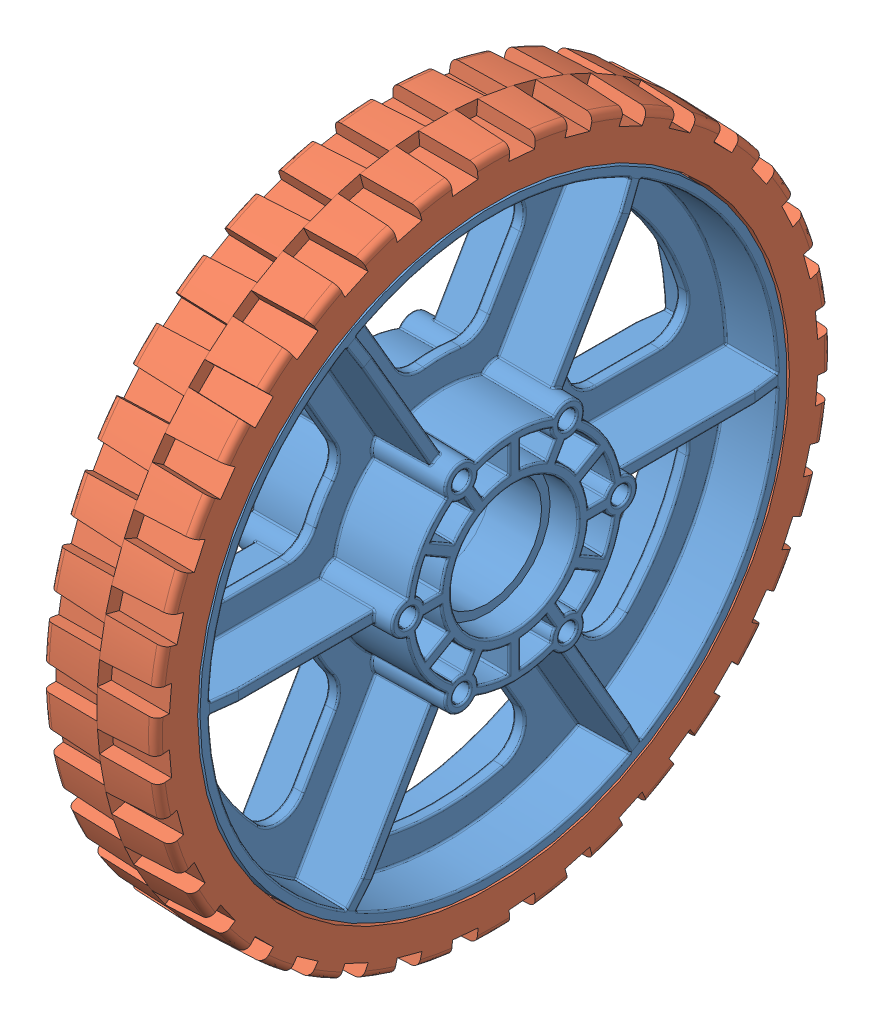
SolidWorks assembly 6 HiGrip Wheel Assembly Rev II, configuration Default. Lengths in mm.
Overall size (34.93 152.4 152.4).
2 component instances, 2 part files, 0 mates.
Components (placement in the parent):
- 6 wheel Rev 4-1: 6 wheel Rev 4 [Default] at (-52.6446 9.4231 21.378) size (34.93 132.08 132.08)
- 6 wheel tread II-1: 6 wheel tread II [Default] at (-65.3446 9.4231 21.378) x (0 0 -1) z (1 0 0) size (152.4 152.4 25.58)
